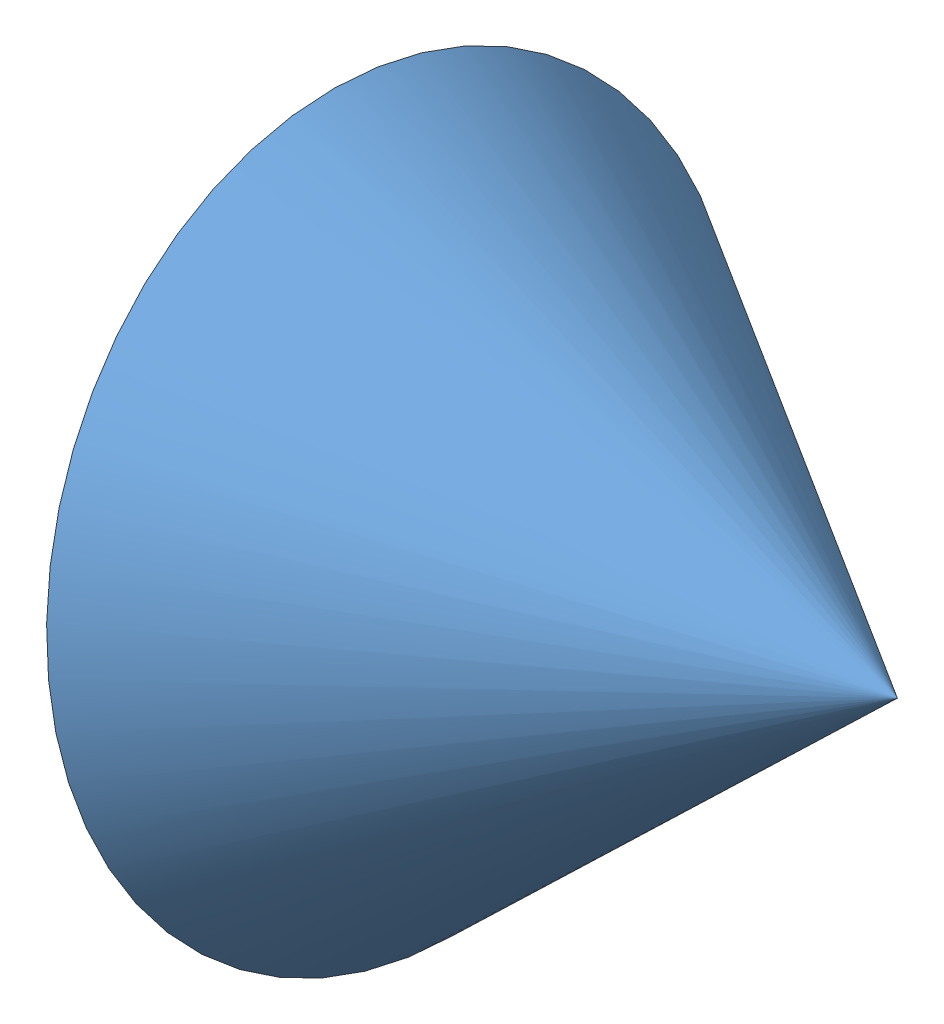
SolidWorks assembly Assem1, configuration Default. Lengths in mm.
Overall size (1227.04 348.58 197.92).
2 component instances, 2 part files, 6 mates.
Components (placement in the parent):
- Part2^Assem1-1: Part2^Assem1 [Default] at origin size (1227.04 261.29 0) (virtual)
- Part1-1: Part1 [Default] at (607.1365 108.0501 0) x (0.122074 -0.677692 -0.725142) z (0.128553 -0.713656 0.688599) size (140 105 140)
Mates (geometry in assembly coordinates):
- InPlace1: in place: plane of Part2^Assem1-1 through (0 0 0) normal (0 0 1); moOrthogonalPlaneRef_w of Part2^Assem1-1 through (0 0 0) normal (0 1 0); plane of Part2^Assem1-1 through (0 0 0) normal (1 0 0); unknown of Part2^Assem1-1
- Coincident1: coincident aligned: 
- Coincident2: coincident aligned: plane of Part2^Assem1-1 through (0 0 0) normal (0 1 0)
- Coincident3: coincident anti-aligned: plane of Part2^Assem1-1 through (0 0 0) normal (1 0 0)
- PathMate1: path: point of Part1-1; curve of Part2^Assem1-1
- Coincident4: coincident: point of assembly; curve of Part2^Assem1-1; point of Part1-1
